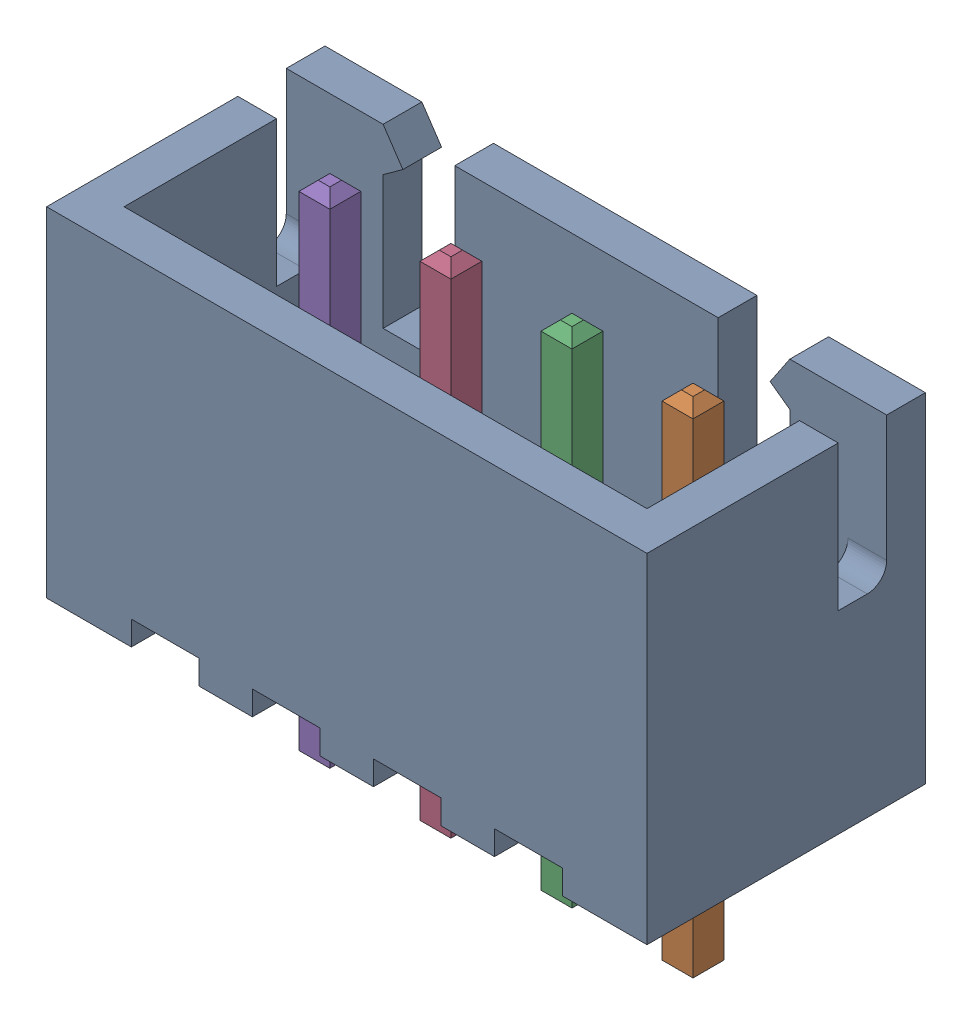
SolidWorks assembly 4 pin Header_3, configuration 4 pin Header_3. Lengths in mm.
Overall size (12.4 10.4 5.75).
5 component instances, 2 part files, 0 mates.
Components (placement in the parent):
- B4B-XH-A (BODY)-1: B4B-XH-A (BODY) [B4B-XH-A (BODY)] at (1.9192 5.3562 13.8157) size (12.4 7 5.75)
- B4B-XH-A (PIN)-1: B4B-XH-A (PIN) [B4B-XH-A (PIN)] at (5.6692 12.3562 13.2907) x (-1 0 0) z (0 0 1) size (0.64 10.4 0.64)
- B4B-XH-A (PIN)-2: B4B-XH-A (PIN) [B4B-XH-A (PIN)] at (3.1692 12.3562 13.2907) x (-1 0 0) z (0 0 1) size (0.64 10.4 0.64)
- B4B-XH-A (PIN)-3: B4B-XH-A (PIN) [B4B-XH-A (PIN)] at (0.6692 12.3562 13.2907) x (-1 0 0) z (0 0 1) size (0.64 10.4 0.64)
- B4B-XH-A (PIN)-4: B4B-XH-A (PIN) [B4B-XH-A (PIN)] at (-1.8308 12.3562 13.2907) x (-1 0 0) z (0 0 1) size (0.64 10.4 0.64)
